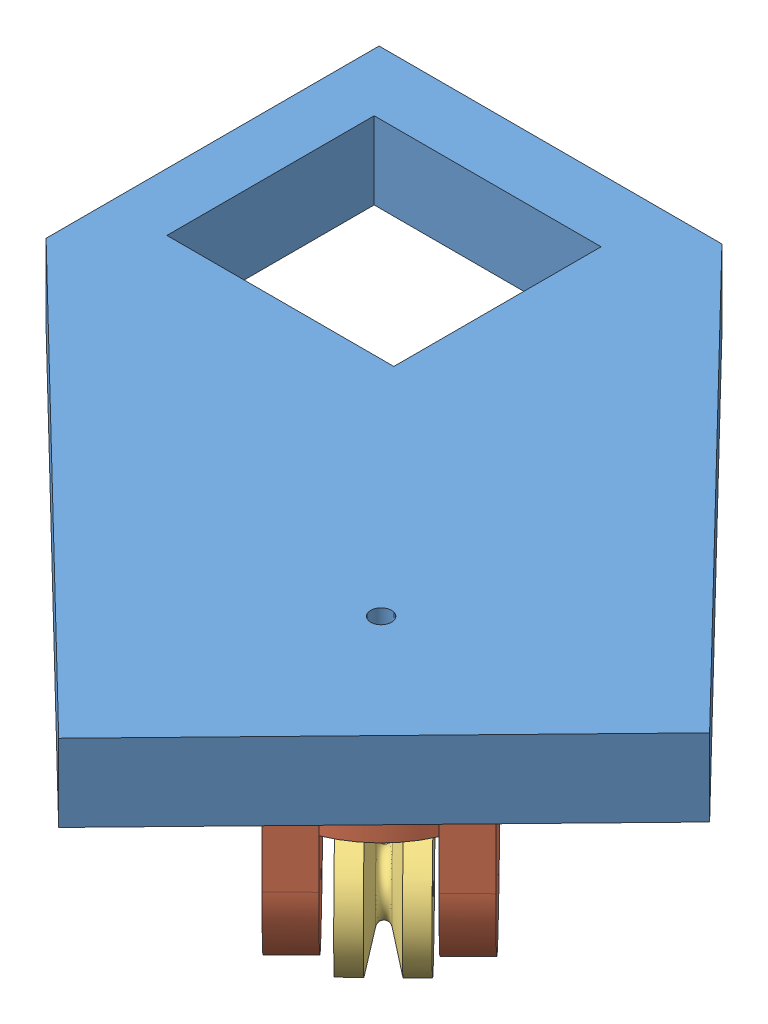
SolidWorks assembly pulleyAssembly, configuration Default. Lengths in mm.
Overall size (196.78 99.24 196.7).
3 component instances, 3 part files, 4 mates.
Components (placement in the parent):
- pulleyTable-1: pulleyTable [Default] at (-56.9922 -8.2808 -54.8373) size (196.78 99.24 196.7)
- support pulley-1: support pulley [Default] at (26.7669 -18.2808 29.6627) x (0.717309 0 -0.696755) z (0.696755 0 0.717309) size (58.88 50 58.88)
- pulley-1: pulley [Default] at (20.7203 -47.8653 35.536) x (0.717309 0 -0.696755) z (0.694961 -0.071716 0.715462) size (18 35 35)
Mates (geometry in assembly coordinates):
- Concentric1: concentric aligned: cylinder of pulleyTable-1 through (26.7669 -8.2808 29.6627) axis (0 1 0) radius 2.7; cylinder of support pulley-1 through (26.7669 -88.2808 29.6627) axis (0 1 0) radius 2.7
- Coincident1: coincident anti-aligned: plane of pulleyTable-1 through (-56.9922 -8.2808 -54.8373) normal (0 -1 0); plane of support pulley-1 through (26.7669 -8.2808 29.6627) normal (0 1 0)
- Parallel1: parallel aligned: plane of pulleyTable-1 through (-12.6122 11.7192 -97.9457) normal (0.717309 0 -0.696755); plane of support pulley-1 through (61.1473 47.3188 34.3386) normal (0.717309 0 -0.696755)
- Concentric2: concentric aligned: cylinder of support pulley-1 through (-15.265 -47.8653 70.4902) axis (0.717309 0 -0.696755) radius 2.7; cylinder of pulley-1 through (20.7203 -47.8653 35.536) axis (0.717309 0 -0.696755) radius 2.7
